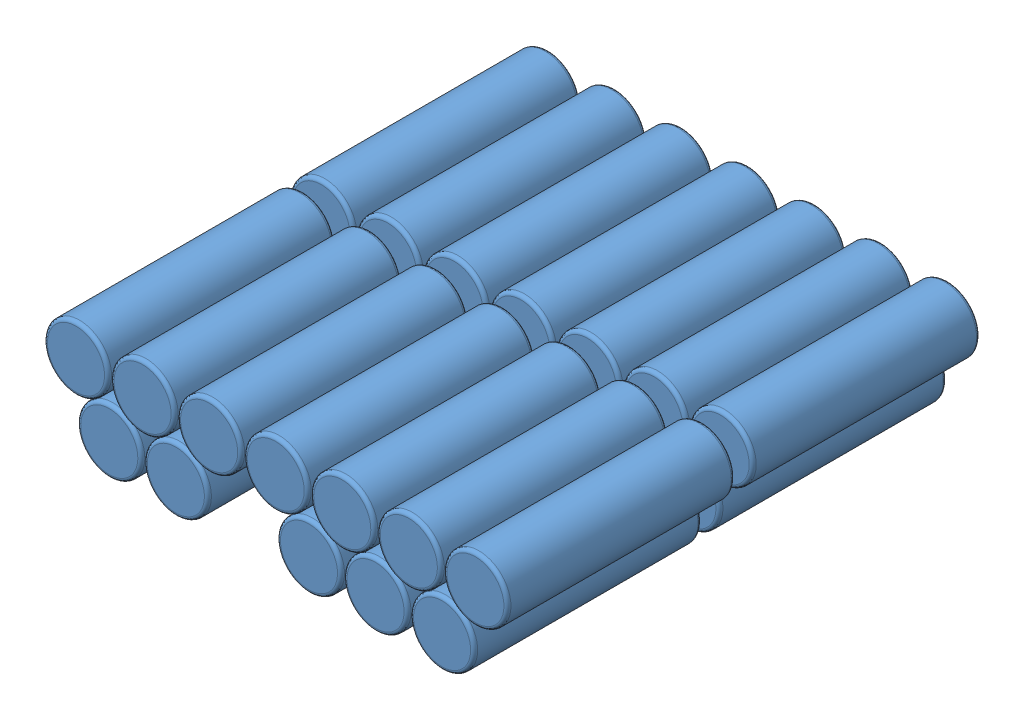
SolidWorks assembly Assem 18650 mock pack, configuration Default. Lengths in mm.
Overall size (138.41 40.78 134.9).
24 component instances, 1 part files, 10 mates.
Components (placement in the parent):
- 18650 battery-1: 18650 battery [Default] at (0 0 -104.1102) x (-0.901839 -0.432072 0) z (-0.432072 0.901839 0) size (18.3 64.9 18.3)
- 18650 battery-2: 18650 battery [Default] at (-19 0 -104.1102) x (-0.901839 -0.432072 0) z (-0.432072 0.901839 0) size (18.3 64.9 18.3)
- 18650 battery-3: 18650 battery [Default] at (-38 0 -104.1102) x (-0.901839 -0.432072 0) z (-0.432072 0.901839 0) size (18.3 64.9 18.3)
- 18650 battery-4: 18650 battery [Default] at (-57 0 -104.1102) x (-0.901839 -0.432072 0) z (-0.432072 0.901839 0) size (18.3 64.9 18.3)
- 18650 battery-5: 18650 battery [Default] at (-76 0 -104.1102) x (-0.901839 -0.432072 0) z (-0.432072 0.901839 0) size (18.3 64.9 18.3)
- 18650 battery-6: 18650 battery [Default] at (-9.5 -15.641 -39.2102) x (0.68708 -0.726582 0) z (0.726582 0.68708 0) size (18.3 64.9 18.3)
- 18650 battery-7: 18650 battery [Default] at (-28.5 -15.641 -39.2102) x (0.68708 -0.726582 0) z (0.726582 0.68708 0) size (18.3 64.9 18.3)
- 18650 battery-8: 18650 battery [Default] at (-47.5 -15.641 -39.2102) x (0.68708 -0.726582 0) z (0.726582 0.68708 0) size (18.3 64.9 18.3)
- 18650 battery-12: 18650 battery [Default] at (-95 0 -104.1102) x (-0.901839 -0.432072 0) z (-0.432072 0.901839 0) size (18.3 64.9 18.3)
- 18650 battery-20: 18650 battery [Default] at (-9.5 -15.641 30.7898) x (0.68708 -0.726582 0) z (0.726582 0.68708 0) size (18.3 64.9 18.3)
- 18650 battery-21: 18650 battery [Default] at (-28.5 -15.641 30.7898) x (0.68708 -0.726582 0) z (0.726582 0.68708 0) size (18.3 64.9 18.3)
- 18650 battery-22: 18650 battery [Default] at (-47.5 -15.641 30.7898) x (0.68708 -0.726582 0) z (0.726582 0.68708 0) size (18.3 64.9 18.3)
- 18650 battery-26: 18650 battery [Default] at (0 0 -34.1102) x (-0.901839 -0.432072 0) z (-0.432072 0.901839 0) size (18.3 64.9 18.3)
- 18650 battery-27: 18650 battery [Default] at (-19 0 -34.1102) x (-0.901839 -0.432072 0) z (-0.432072 0.901839 0) size (18.3 64.9 18.3)
- 18650 battery-28: 18650 battery [Default] at (-38 0 -34.1102) x (-0.901839 -0.432072 0) z (-0.432072 0.901839 0) size (18.3 64.9 18.3)
- 18650 battery-29: 18650 battery [Default] at (-57 0 -34.1102) x (-0.901839 -0.432072 0) z (-0.432072 0.901839 0) size (18.3 64.9 18.3)
- 18650 battery-30: 18650 battery [Default] at (-76 0 -34.1102) x (-0.901839 -0.432072 0) z (-0.432072 0.901839 0) size (18.3 64.9 18.3)
- 18650 battery-31: 18650 battery [Default] at (-95 0 -34.1102) x (-0.901839 -0.432072 0) z (-0.432072 0.901839 0) size (18.3 64.9 18.3)
- 18650 battery-32: 18650 battery [Default] at (-114 0 -104.1102) x (-0.901839 -0.432072 0) z (-0.432072 0.901839 0) size (18.3 64.9 18.3)
- 18650 battery-33: 18650 battery [Default] at (-114 0 -34.1102) x (-0.901839 -0.432072 0) z (-0.432072 0.901839 0) size (18.3 64.9 18.3)
- 18650 battery-34: 18650 battery [Default] at (-104.5 -15.641 -104.1102) x (-0.103838 0.994594 0) z (0.994594 0.103838 0) size (18.3 64.9 18.3)
- 18650 battery-35: 18650 battery [Default] at (-85.5 -15.641 -104.1102) x (-0.103838 0.994594 0) z (0.994594 0.103838 0) size (18.3 64.9 18.3)
- 18650 battery-36: 18650 battery [Default] at (-104.5 -15.641 -34.1102) x (-0.103838 0.994594 0) z (0.994594 0.103838 0) size (18.3 64.9 18.3)
- 18650 battery-37: 18650 battery [Default] at (-85.5 -15.641 -34.1102) x (-0.103838 0.994594 0) z (0.994594 0.103838 0) size (18.3 64.9 18.3)
Mates (geometry in assembly coordinates):
- Parallel1: parallel anti-aligned: plane of 18650 battery-1 through (0 0 -104.1102) normal (0 0 -1); plane of assembly through (0 0 0) normal (0 0 1)
- Coincident4: coincident: axis of 18650 battery-1 through (0 0 -40.2102) axis (0 0 -1); point of assembly
- Tangent6: tangent anti-aligned: cylinder of 18650 battery-1 through (0 0 -39.2102) axis (0 0 -1) radius 9.15; cylinder of 18650 battery-6 through (-9.5 -15.641 -104.1102) axis (0 0 1) radius 9.15
- Parallel3: parallel anti-aligned: cylinder of 18650 battery-1 through (0 0 -39.2102) axis (0 0 -1) radius 9.15; cylinder of 18650 battery-6 through (-9.5 -15.641 -104.1102) axis (0 0 1) radius 9.15
- Tangent7: tangent anti-aligned: cylinder of 18650 battery-2 through (-19 0 -39.2102) axis (0 0 -1) radius 9.15; cylinder of 18650 battery-6 through (-9.5 -15.641 -104.1102) axis (0 0 1) radius 9.15
- Coincident5: coincident aligned: plane of 18650 battery-1 through (0 0 -104.1102) normal (0 0 -1); plane of 18650 battery-6 through (-9.5 -15.641 -104.1102) normal (0 0 -1)
- Tangent14: tangent anti-aligned: cylinder of 18650 battery-32 through (-114 0 -39.2102) axis (0 0 -1) radius 9.15; cylinder of 18650 battery-34 through (-104.5 -15.641 -39.2102) axis (0 0 -1) radius 9.15
- Parallel4: parallel aligned: cylinder of 18650 battery-32 through (-114 0 -39.2102) axis (0 0 -1) radius 9.15; cylinder of 18650 battery-34 through (-104.5 -15.641 -39.2102) axis (0 0 -1) radius 9.15
- Tangent15: tangent anti-aligned: cylinder of 18650 battery-12 through (-95 0 -39.2102) axis (0 0 -1) radius 9.15; cylinder of 18650 battery-34 through (-104.5 -15.641 -39.2102) axis (0 0 -1) radius 9.15
- Coincident6: coincident aligned: plane of 18650 battery-32 through (-114 0 -104.1102) normal (0 0 -1); plane of 18650 battery-34 through (-104.5 -15.641 -104.1102) normal (0 0 -1)
